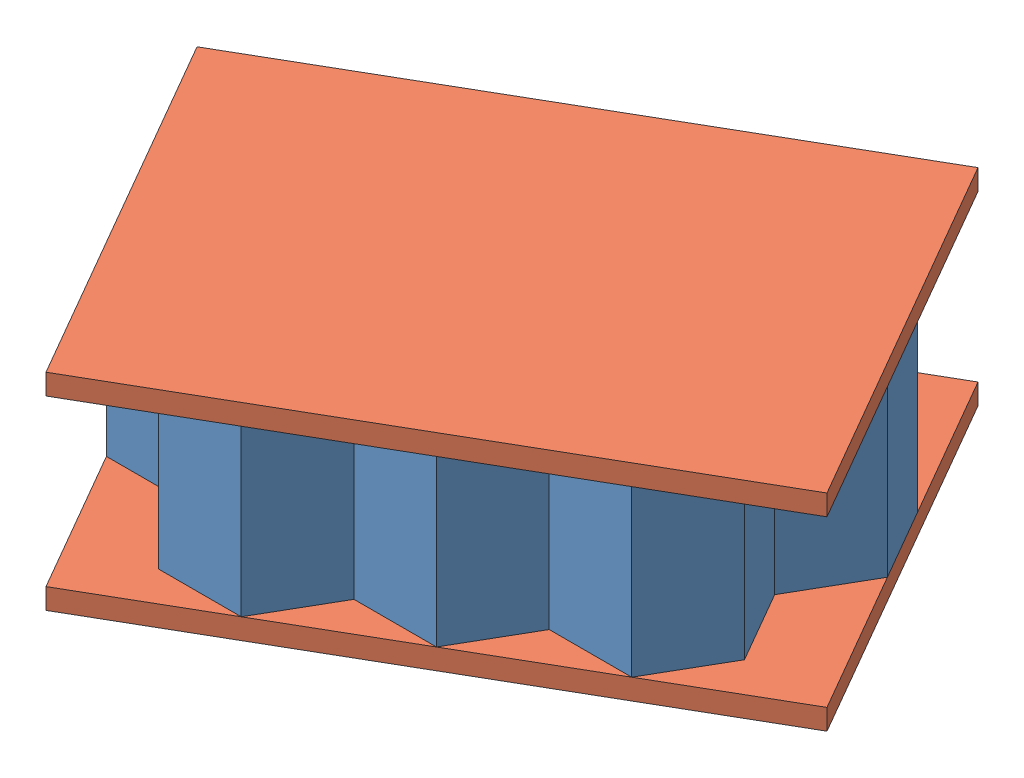
SolidWorks assembly Assem1, configuration Default. Lengths in mm.
Overall size (215.9 63.5 197.97).
12 component instances, 2 part files, 36 mates.
Components (placement in the parent):
- SandwichPanelHexagon-1: SandwichPanelHexagon [Default] at (-58.5038 -21.5104 56.9278) size (50.8 50.8 43.99)
- SandwichPanelHexagon-2: SandwichPanelHexagon [Default] at (-20.4038 -21.5104 78.9248) size (50.8 50.8 43.99)
- SandwichPanelHexagon-3: SandwichPanelHexagon [Default] at (-20.4038 -21.5104 34.9308) size (50.8 50.8 43.99)
- SandwichPanelHexagon-4: SandwichPanelHexagon [Default] at (17.6962 -21.5104 56.9278) size (50.8 50.8 43.99)
- SandwichPanelHexagon-5: SandwichPanelHexagon [Default] at (-96.6038 -21.5104 78.9248) size (50.8 50.8 43.99)
- SandwichPanelHexagon-6: SandwichPanelHexagon [Default] at (-58.5038 -21.5104 100.9219) size (50.8 50.8 43.99)
- SandwichPanelHexagon-7: SandwichPanelHexagon [Default] at (-58.5038 -21.5104 144.916) size (50.8 50.8 43.99)
- SandwichPanelHexagon-8: SandwichPanelHexagon [Default] at (17.6962 -21.5104 100.9219) size (50.8 50.8 43.99)
- SandwichPanelHexagon-9: SandwichPanelHexagon [Default] at (-96.6038 -21.5104 122.9189) size (50.8 50.8 43.99)
- SandwichPanelHexagon-11: SandwichPanelHexagon [Default] at (-20.4038 -21.5104 122.9189) size (50.8 50.8 43.99)
- SandwichPanelPlates-3: SandwichPanelPlates [Default] at (55.7961 29.2896 78.9249) x (0.866025 0 -0.5) z (0.5 0 0.866025) size (175.98 6.35 127)
- SandwichPanelPlates-4: SandwichPanelPlates [Default] at (55.7961 -27.8604 78.9249) x (0.866025 0 -0.5) z (0.5 0 0.866025) size (175.98 6.35 127)
Mates (geometry in assembly coordinates):
- Coincident1: coincident anti-aligned: plane of SandwichPanelHexagon-1 through (-58.5038 29.2896 56.9278) normal (0.866025 0 0.5); plane of SandwichPanelHexagon-2 through (-45.8038 29.2896 34.9308) normal (-0.866025 0 -0.5)
- Coincident2: coincident aligned: line of SandwichPanelHexagon-1 through (-58.5038 29.2896 56.9278) axis (0 -1 0); line of SandwichPanelHexagon-2 through (-58.5038 29.2896 56.9278) axis (0 -1 0)
- Coincident3: coincident aligned: plane of SandwichPanelHexagon-1 through (-58.5038 29.2896 56.9278) normal (0 1 0); plane of SandwichPanelHexagon-2 through (-20.4038 29.2896 78.9248) normal (0 1 0)
- Coincident4: coincident anti-aligned: plane of SandwichPanelHexagon-1 through (-58.5038 29.2896 56.9278) normal (0 0 1); plane of SandwichPanelHexagon-6 through (-58.5038 29.2896 56.9278) normal (0 0 -1)
- Coincident6: coincident anti-aligned: plane of SandwichPanelHexagon-1 through (-58.5038 29.2896 56.9278) normal (0 0 1); plane of SandwichPanelHexagon-6 through (-58.5038 29.2896 56.9278) normal (0 0 -1)
- Coincident7: coincident anti-aligned: plane of SandwichPanelHexagon-2 through (-58.5038 29.2896 56.9278) normal (-0.866025 0 0.5); plane of SandwichPanelHexagon-6 through (-58.5038 29.2896 56.9278) normal (0.866025 0 -0.5)
- Coincident8: coincident aligned: plane of SandwichPanelHexagon-2 through (-20.4038 29.2896 78.9248) normal (0 1 0); plane of SandwichPanelHexagon-6 through (-58.5038 29.2896 100.9219) normal (0 1 0)
- Coincident9: coincident anti-aligned: plane of SandwichPanelHexagon-1 through (-58.5038 29.2896 12.9337) normal (0.866025 0 -0.5); plane of SandwichPanelHexagon-3 through (-58.5038 29.2896 12.9337) normal (-0.866025 0 0.5)
- Coincident10: coincident anti-aligned: plane of SandwichPanelHexagon-2 through (-20.4038 29.2896 34.9308) normal (0 0 -1); plane of SandwichPanelHexagon-3 through (-20.4038 29.2896 34.9308) normal (0 0 1)
- Coincident11: coincident aligned: plane of SandwichPanelHexagon-2 through (-20.4038 29.2896 78.9248) normal (0 1 0); plane of SandwichPanelHexagon-3 through (-20.4038 29.2896 34.9308) normal (0 1 0)
- Coincident12: coincident anti-aligned: plane of SandwichPanelHexagon-5 through (-96.6038 29.2896 78.9248) normal (0.866025 0 0.5); plane of SandwichPanelHexagon-6 through (-83.9038 29.2896 56.9278) normal (-0.866025 0 -0.5)
- Coincident13: coincident anti-aligned: plane of SandwichPanelHexagon-1 through (-96.6038 29.2896 34.9308) normal (-0.866025 0 0.5); plane of SandwichPanelHexagon-5 through (-96.6038 29.2896 34.9308) normal (0.866025 0 -0.5)
- Coincident14: coincident aligned: plane of SandwichPanelHexagon-5 through (-96.6038 29.2896 78.9248) normal (0 1 0); plane of SandwichPanelHexagon-6 through (-58.5038 29.2896 100.9219) normal (0 1 0)
- Coincident15: coincident anti-aligned: plane of SandwichPanelHexagon-2 through (-20.4038 29.2896 34.9308) normal (0.866025 0 -0.5); plane of SandwichPanelHexagon-4 through (-20.4038 29.2896 34.9308) normal (-0.866025 0 0.5)
- Coincident16: coincident anti-aligned: plane of SandwichPanelHexagon-3 through (-20.4038 29.2896 34.9308) normal (0.866025 0 0.5); plane of SandwichPanelHexagon-4 through (-7.7038 29.2896 12.9337) normal (-0.866025 0 -0.5)
- Coincident17: coincident aligned: plane of SandwichPanelHexagon-2 through (-20.4038 29.2896 78.9248) normal (0 1 0); plane of SandwichPanelHexagon-4 through (17.6962 29.2896 56.9278) normal (0 1 0)
- Coincident18: coincident anti-aligned: plane of SandwichPanelHexagon-6 through (-58.5038 29.2896 100.9219) normal (0 0 1); plane of SandwichPanelHexagon-7 through (-58.5038 29.2896 100.9219) normal (0 0 -1)
- Coincident19: coincident aligned: line of SandwichPanelHexagon-6 through (-58.5038 29.2896 100.9219) axis (0 -1 0); line of SandwichPanelHexagon-7 through (-58.5038 29.2896 100.9219) axis (0 -1 0)
- Coincident20: coincident aligned: plane of SandwichPanelHexagon-6 through (-58.5038 29.2896 100.9219) normal (0 1 0); plane of SandwichPanelHexagon-7 through (-58.5038 29.2896 144.916) normal (0 1 0)
- Coincident21: coincident anti-aligned: plane of SandwichPanelHexagon-7 through (-58.5038 29.2896 100.9219) normal (0.866025 0 -0.5); plane of SandwichPanelHexagon-11 through (-58.5038 29.2896 100.9219) normal (-0.866025 0 0.5)
- Coincident22: coincident anti-aligned: plane of SandwichPanelHexagon-2 through (-20.4038 29.2896 78.9248) normal (0 0 1); plane of SandwichPanelHexagon-11 through (-20.4038 29.2896 78.9248) normal (0 0 -1)
- Coincident23: coincident aligned: plane of SandwichPanelHexagon-6 through (-58.5038 29.2896 100.9219) normal (0 1 0); plane of SandwichPanelHexagon-11 through (-20.4038 29.2896 122.9189) normal (0 1 0)
- Coincident24: coincident anti-aligned: plane of SandwichPanelHexagon-2 through (-20.4038 29.2896 78.9248) normal (0.866025 0 0.5); plane of SandwichPanelHexagon-8 through (-7.7038 29.2896 56.9278) normal (-0.866025 0 -0.5)
- Coincident25: coincident anti-aligned: plane of SandwichPanelHexagon-8 through (-20.4038 29.2896 78.9248) normal (-0.866025 0 0.5); plane of SandwichPanelHexagon-11 through (-20.4038 29.2896 78.9248) normal (0.866025 0 -0.5)
- Coincident26: coincident aligned: plane of SandwichPanelHexagon-2 through (-20.4038 29.2896 78.9248) normal (0 1 0); plane of SandwichPanelHexagon-8 through (17.6962 29.2896 100.9219) normal (0 1 0)
- Coincident27: coincident anti-aligned: plane of SandwichPanelHexagon-7 through (-83.9038 29.2896 100.9219) normal (-0.866025 0 -0.5); plane of SandwichPanelHexagon-9 through (-96.6038 29.2896 122.9189) normal (0.866025 0 0.5)
- Coincident28: coincident anti-aligned: plane of SandwichPanelHexagon-6 through (-96.6038 29.2896 78.9248) normal (-0.866025 0 0.5); plane of SandwichPanelHexagon-9 through (-96.6038 29.2896 78.9248) normal (0.866025 0 -0.5)
- Coincident29: coincident aligned: plane of SandwichPanelHexagon-6 through (-58.5038 29.2896 100.9219) normal (0 1 0); plane of SandwichPanelHexagon-9 through (-96.6038 29.2896 122.9189) normal (0 1 0)
- Coincident40: coincident: line of SandwichPanelHexagon-9 through (-134.7038 29.2896 100.9219) axis (0.5 0 0.866025); plane of SandwichPanelPlates-3 through (-96.6038 35.6396 166.913) normal (-0.866025 0 0.5)
- Coincident41: coincident: point of SandwichPanelHexagon-11; plane of SandwichPanelPlates-3 through (55.7961 35.6396 78.9249) normal (0.5 0 0.866025)
- Coincident42: coincident: line of SandwichPanelHexagon-9 through (-134.7038 29.2896 100.9219) axis (0.5 0 0.866025); plane of SandwichPanelPlates-3 through (-96.6038 35.6396 166.913) normal (-0.866025 0 0.5)
- Coincident43: coincident anti-aligned: plane of SandwichPanelHexagon-7 through (-58.5038 29.2896 144.916) normal (0 1 0); plane of SandwichPanelPlates-3 through (55.7961 29.2896 78.9249) normal (0 -1 0)
- Coincident44: coincident: point of SandwichPanelHexagon-11; plane of SandwichPanelPlates-3 through (55.7961 35.6396 78.9249) normal (0.5 0 0.866025)
- Coincident45: coincident anti-aligned: plane of SandwichPanelHexagon-6 through (-58.5038 -21.5104 100.9219) normal (0 -1 0); plane of SandwichPanelPlates-4 through (55.7961 -21.5104 78.9249) normal (0 1 0)
- Coincident46: coincident: line of SandwichPanelHexagon-9 through (-134.7038 -21.5104 100.9219) axis (0.5 0 0.866025); plane of SandwichPanelPlates-4 through (-96.6038 -21.5104 166.913) normal (-0.866025 0 0.5)
- Coincident47: coincident: point of SandwichPanelHexagon-11; plane of SandwichPanelPlates-4 through (55.7961 -21.5104 78.9249) normal (0.5 0 0.866025)
